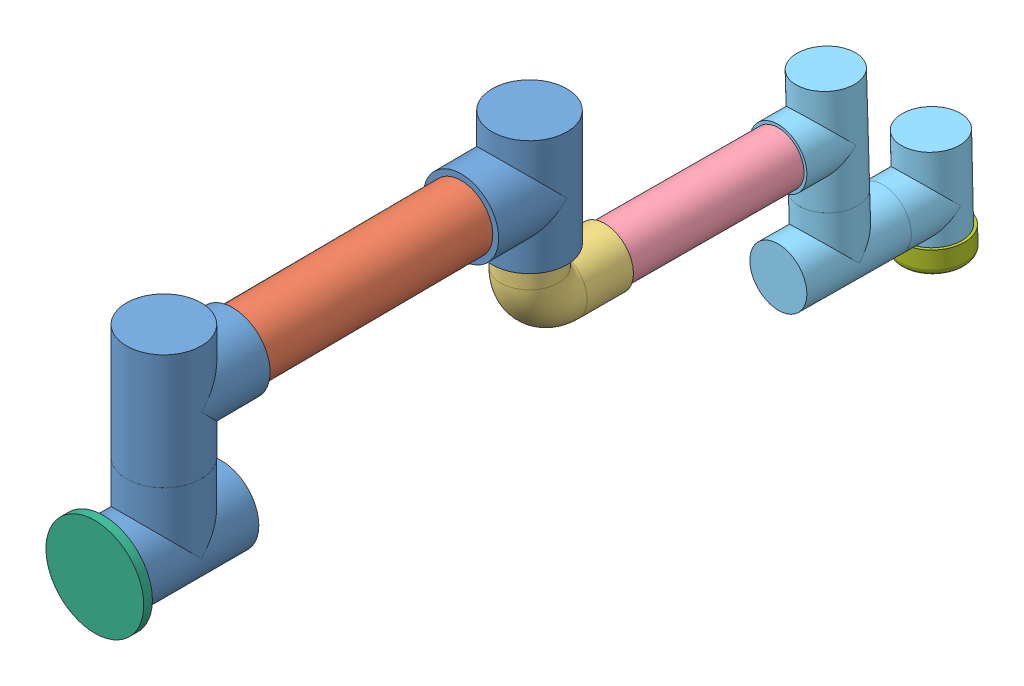
SolidWorks assembly aubo2, configuration Default. Lengths in mm.
Overall size (194.87 553.2 1504.94).
11 component instances, 7 part files, 20 mates.
Components (placement in the parent):
- 3RAH 90-1: 3RAH 90 [Default] at (-212.2486 38.1396 349.9086) size (130 185 200)
- 3RAH 90-2: 3RAH 90 [Default] at (-212.2486 208.1396 299.9086) x (-0.999976 0 0.006961) z (0 -1 0) size (130 185 200)
- Part3-1: Part3 [Default] at (-213.0839 258.1396 179.9115) x (-0.006961 0 -0.999976) z (-0.871518 0.490326 0.006066) size (400 110 110)
- 3RAH 90-3: 3RAH 90 [Default] at (-216.7255 308.1396 -340.0757) x (-0.999976 -0.000443 0.006961) z (-0.000443 1 0.000003) size (130 185 200)
- Part1-1: Part1 [Default] at (-216.1661 73.1401 -430.0753) x (0.005058 0.000005 -0.999987) z (0.000443 -1 -0.000003) size (180 100 135)
- D100 L400-1: D100 L400 [Default] at (-215.9637 73.1403 -470.0748) x (-0.946691 -0.322108 -0.00479) z (0.322104 -0.946703 0.001624) size (90 300 90)
- Part2-4: Part2 [Default] at (-208.8838 -101.7758 -810.0446) x (0.999462 0.031593 0.008805) z (-0.008805 -0.000124 0.999961) size (100 135 180)
- Part2-5: Part2 [Default] at (-212.5947 28.1649 -855.0629) x (0.999488 0.031594 0.005056) z (0.031593 -0.999501 0.000154) size (100 135 180)
- Part2-6: Part2 [Default] at (-205.8792 -146.7359 -1030.0322) x (0.99968 0.023721 0.008806) z (0.023721 -0.999719 0.000085) size (100 135 180)
- kafi-1: kafi [Default] at (-212.2486 38.1396 404.9086) x (0.987275 -0.159024 0) z (0.159024 0.987275 0) size (170 20 170)
- cover3-1: cover3 [Default] at (-205.7132 -153.734 -1030.0316) x (0.023721 -0.999719 0.000085) z (-0.000085 0.000083 1) size (40 110 110)
Mates (geometry in assembly coordinates):
- Coincident1: coincident aligned: line of 3RAH 90-1 through (-212.2486 38.1396 299.9086) axis (0 1 0); line of 3RAH 90-2 through (-212.2486 158.1396 299.9086) axis (0 1 0)
- Coincident2: coincident anti-aligned: plane of 3RAH 90-1 through (-212.2486 158.1396 299.9086) normal (0 1 0); plane of 3RAH 90-2 through (-212.2486 158.1396 299.9086) normal (0 -1 0)
- Coincident3: coincident anti-aligned: line of 3RAH 90-2 through (-212.2486 258.1396 299.9086) axis (-0.006961 0 -0.999976); line of Part3-1 through (-215.8681 258.1396 -220.0788) axis (0.006961 0 0.999976)
- Coincident4: coincident anti-aligned: plane of 3RAH 90-2 through (-213.0839 258.1396 179.9115) normal (-0.006961 0 -0.999976); plane of Part3-1 through (-213.0839 258.1396 179.9115) normal (0.006961 0 0.999976)
- Coincident5: coincident aligned: line of Part3-1 through (-215.8681 258.1396 -220.0788) axis (0.006961 0 0.999976); line of 3RAH 90-3 through (-216.7033 258.1396 -340.0759) axis (0.006961 0 0.999976)
- Coincident6: coincident anti-aligned: plane of Part3-1 through (-215.8681 258.1396 -220.0788) normal (-0.006961 0 -0.999976); plane of 3RAH 90-3 through (-215.8681 258.1396 -220.0788) normal (0.006961 0 0.999976)
- Coincident7: coincident aligned: line of 3RAH 90-3 through (-216.7477 358.1396 -340.0756) axis (0.000443 -1 -0.000003); line of Part1-1 through (-216.659 158.1396 -340.0762) axis (0.000443 -1 -0.000003)
- Coincident8: coincident anti-aligned: plane of 3RAH 90-3 through (-216.659 158.1396 -340.0762) normal (0.000443 -1 -0.000003); plane of Part1-1 through (-216.659 158.1396 -340.0762) normal (-0.000443 1 0.000003)
- Coincident9: coincident anti-aligned: line of Part1-1 through (-216.3684 73.1399 -390.0758) axis (0.005058 0.000005 -0.999987); line of D100 L400-1 through (-214.4463 73.1419 -770.0709) axis (-0.005058 -0.000005 0.999987)
- Coincident10: coincident anti-aligned: plane of Part1-1 through (-215.9637 73.1403 -470.0748) normal (0.005058 0.000005 -0.999987); plane of D100 L400-1 through (-215.9637 73.1403 -470.0748) normal (-0.005058 -0.000005 0.999987)
- Coincident11: coincident aligned: line of D100 L400-1 through (-214.4463 73.1419 -770.0709) axis (-0.005058 -0.000005 0.999987); line of Part2-5 through (-214.0164 73.1424 -855.0699) axis (-0.005058 -0.000005 0.999987)
- Coincident12: coincident anti-aligned: plane of D100 L400-1 through (-214.4463 73.1419 -770.0709) normal (0.005058 0.000005 -0.999987); plane of Part2-5 through (-214.4463 73.1419 -770.0709) normal (-0.005058 -0.000005 0.999987)
- Coincident13: coincident aligned: line of Part2-4 through (-208.4876 -101.7702 -855.0428) axis (-0.031593 0.999501 -0.000154); line of Part2-5 through (-211.173 -16.8127 -855.056) axis (-0.031593 0.999501 -0.000154)
- Coincident14: coincident anti-aligned: plane of Part2-4 through (-211.173 -16.8127 -855.056) normal (-0.031593 0.999501 -0.000154); plane of Part2-5 through (-211.173 -16.8127 -855.056) normal (0.031593 -0.999501 0.000154)
- Coincident15: coincident anti-aligned: line of Part2-4 through (-209.28 -101.7814 -765.0463) axis (0.008805 0.000124 -0.999961); line of Part2-6 through (-206.9467 -101.7486 -1030.036) axis (-0.008805 -0.000124 0.999961)
- Coincident16: coincident anti-aligned: plane of Part2-4 through (-207.6951 -101.7591 -945.0393) normal (0.008805 0.000124 -0.999961); plane of Part2-6 through (-207.6951 -101.7591 -945.0393) normal (-0.008805 -0.000124 0.999961)
- Coincident19: coincident aligned: line of 3RAH 90-1 through (-212.2486 38.1396 399.9086) axis (0 0 -1); line of kafi-1 through (-212.2486 38.1396 419.9086) axis (0 0 -1)
- Coincident20: coincident anti-aligned: plane of 3RAH 90-1 through (-212.2486 38.1396 399.9086) normal (0 0 1); plane of kafi-1 through (-212.2486 38.1396 399.9086) normal (0 0 -1)
- Coincident21: coincident aligned: line of Part2-6 through (-204.8118 -191.7233 -1030.0284) axis (-0.023721 0.999719 -0.000085); line of cover3-1 through (-205.0015 -183.7255 -1030.0291) axis (-0.023721 0.999719 -0.000085)
- Coincident22: coincident anti-aligned: plane of Part2-6 through (-204.8118 -191.7233 -1030.0284) normal (0.023721 -0.999719 0.000085); plane of cover3-1 through (-204.8118 -191.7233 -1030.0284) normal (-0.023721 0.999719 -0.000085)
